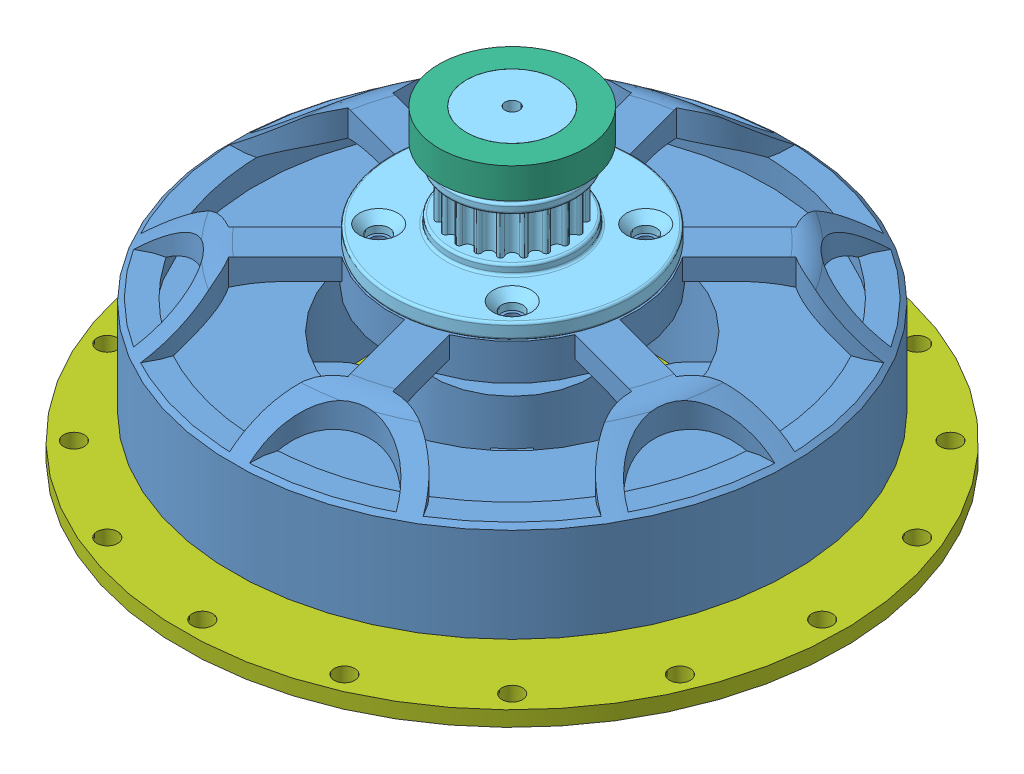
SolidWorks assembly SH Motor Assem, configuration Default. Lengths in mm.
Overall size (129.63 57.83 129.63).
9 component instances, 8 part files, 7 mates.
Components (placement in the parent):
- Motor Assem-1: Motor Assem [Default] at origin size (129.63 44.53 129.63)
  - 9225 160kv-1: 9225 160kv [Default] at (0 -18.055 0) x (0.707107 0 0.707107) z (-0.707107 0 0.707107) size (91.66 44.53 91.66)
  - Encoder Magnet-1: Encoder Magnet [Default] at (0 -19.6425 0) size (6.35 3.17 6.35)
  - Magnut hex puck-1: Magnut hex puck [Default] at (0 -18.055 0) x (0.707107 0 0.707107) z (-0.707107 0 0.707107) size (22.91 4.76 22.91)
  - encoder final board-1: encoder final board [Default] at (0 -23.0237 0) x (0 0 -1) z (1 0 0) size (25 2.95 25)
- Motor Belt Pulley-1: Motor Belt Pulley [Default] at (0 21.7525 0) x (-0.707107 0 -0.707107) z (0.707107 0 -0.707107) size (39.69 19.3 39.69)
- Bearing 15_24_5mm-1: Bearing 15_24_5mm [Default] at (0 30.9275 0) size (24 5 24)
- Motor Baseplate^SH Motor Assem-1: Motor Baseplate^SH Motor Assem [Default] at origin size (108.25 2.5 108.25) (virtual)
- Encoder Mount^SH Motor Assem-1: Encoder Mount^SH Motor Assem [Default] at origin size (49.9 7.4 49.9) (virtual)
Mates (geometry in assembly coordinates):
- Coincident1: coincident aligned: line of Motor Belt Pulley-1 through (6.6 0 25.0525) axis (0 0 -1)
- Concentric1: concentric: cylinder of Motor Assem-1/9225 160kv-1 through (-10.9602 14.125 -10.9602) axis (0 1 0) radius 1.25; cylinder of 15 tooth htd 3mm pulley-1 through (-10.9602 17.8379 -10.9602) axis (0 1 0) radius 1.7463
- Coincident2: coincident anti-aligned: plane of Motor Assem-1/9225 160kv-1 through (22.981 14.125 22.981) normal (0 1 0); plane of Motor Belt Pulley-1 through (0 14.125 0) normal (0 -1 0)
- Coincident4: coincident aligned: plane of Motor Belt Pulley-1 through (0 21.7525 0) normal (1 0 0)
- Coincident5: coincident: point of Bearing 15_24_5mm-1
- Coincident6: coincident anti-aligned: plane of Motor Belt Pulley-1 through (-5.3033 28.4275 5.3033) normal (0 1 0); plane of Bearing 15_24_5mm-1 through (0 28.4275 0) normal (0 -1 0)
- Coincident7: coincident aligned: plane of Bearing 15_24_5mm-1 through (0 30.9275 0) normal (0 0 1)
